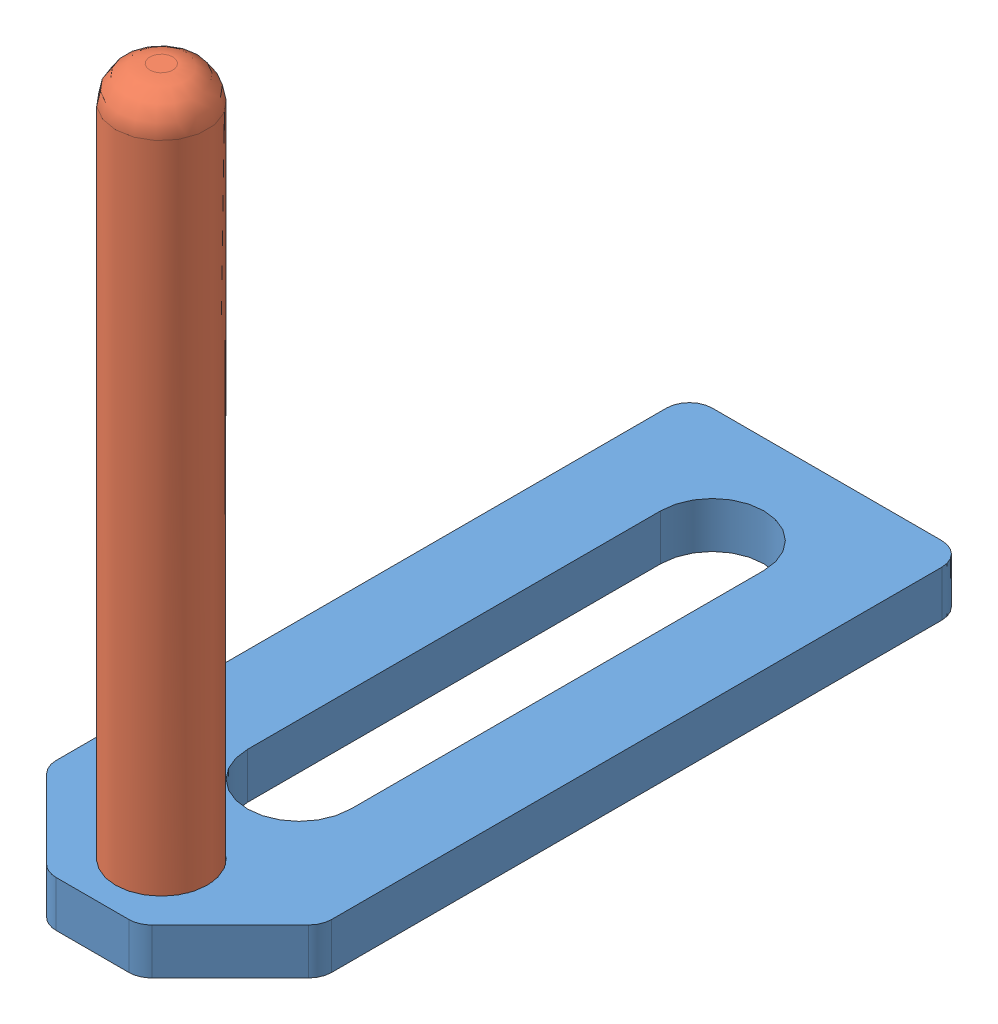
SolidWorks assembly 55CFW-532, configuration Default. Lengths in mm.
Overall size (19.05 50.8 50.8).
2 component instances, 2 part files, 3 mates.
Components (placement in the parent):
- 55CFW-532-C1-1: 55CFW-532-C1 [Default] at origin size (19.05 3.17 50.8)
- 55CFW-532-C2-1: 55CFW-532-C2 [Default] at (0 23.8125 20.6375) size (6.35 50.8 6.35)
Mates (geometry in assembly coordinates):
- Concentric1: concentric anti-aligned: cylinder of 55CFW-532-C1-1 through (0 1.5875 20.6375) axis (0 1 0) radius 3.175; cylinder of 55CFW-532-C2-1 through (0 49.2125 20.6375) axis (0 -1 0) radius 3.175
- Coincident1: coincident aligned: plane of 55CFW-532-C1-1 through (-9.525 -1.5875 25.4) normal (0 -1 0); plane of 55CFW-532-C2-1 through (0 -1.5875 20.6375) normal (0 -1 0)
- Parallel1: parallel aligned: plane of 55CFW-532-C1-1 through (-9.525 -1.5875 25.4) normal (0 0 1); plane of 55CFW-532-C2-1 through (0 23.8125 20.6375) normal (0 0 1)
